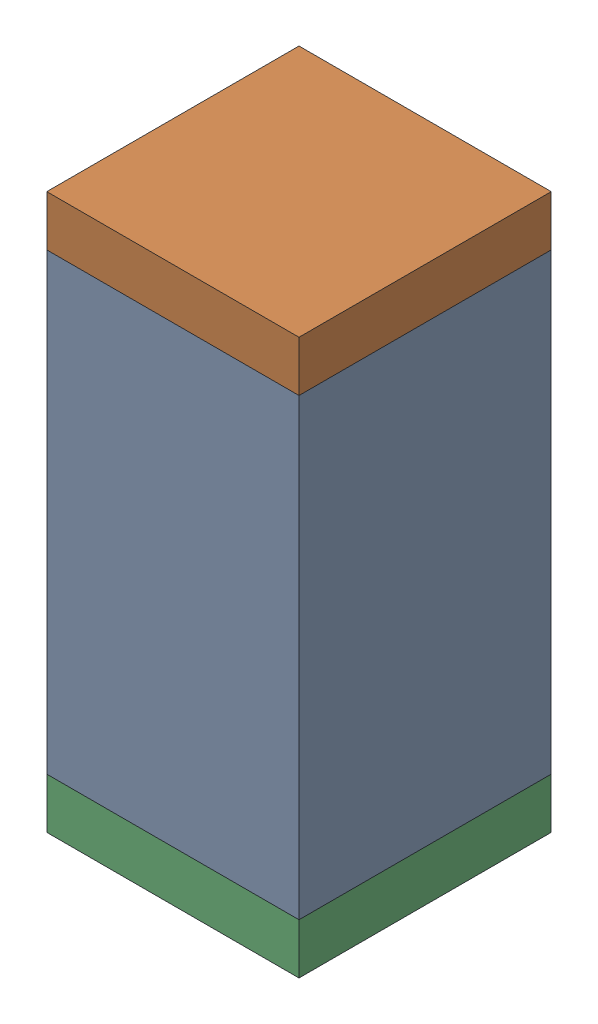
SolidWorks assembly C58, configuration Default. Lengths in mm.
Overall size (0.5 1.1 0.5).
6 component instances, 2 part files, 0 mates.
Components (placement in the parent):
- 791586336-1: 791586336 [Default] at (107.25 51.25 0) size (0.5 0.9 0.5)
  - Extruded_8-1: Extruded_8 [Default] at origin size (0.5 0.9 0.5)
- 810157360-1: 810157360 [Default] at (107.25 51.75 0) size (0.5 0.1 0.5)
  - Extruded_9-1: Extruded_9 [Default] at origin size (0.5 0.1 0.5)
- 810157360-2: 810157360 [Default] at (107.25 50.75 0) size (0.5 0.1 0.5)
  - Extruded_9-1: Extruded_9 [Default] at origin size (0.5 0.1 0.5)
